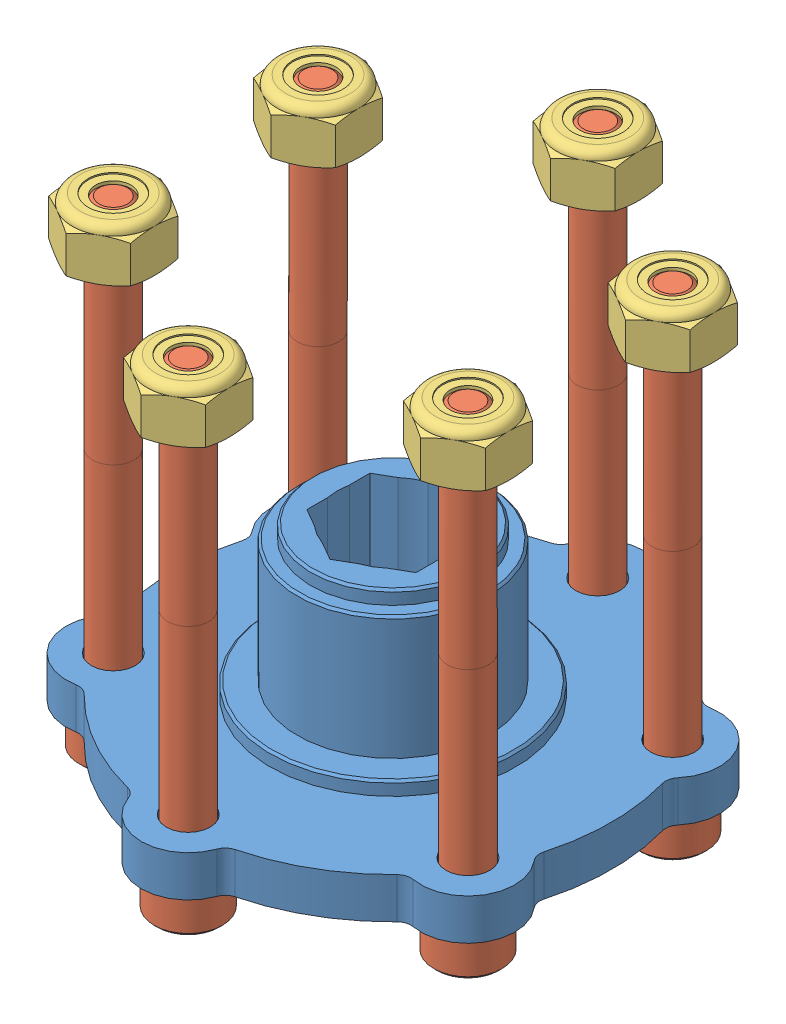
SolidWorks assembly GE-22447, configuration Default. Lengths in mm.
Overall size (76.79 56.16 74.45).
17 component instances, 5 part files, 35 mates.
Components (placement in the parent):
- GE-22446-1: GE-22446 [Default] at origin
  - Tire-1: Tire [Default] x (-1 0 0) z (0 -1 0) (suppressed, hidden)
  - Valve-1: Valve [Default] at (-45.72 0 0) x (-1 0 0) z (0 0 -1) (suppressed, hidden)
  - Pneumatic Hub-1: Pneumatic Hub [Default] at (-1.1351 -5.8811 9.0791) x (0 -1 0) z (0 0 -1) size (45.47 106.55 106.55) (suppressed, hidden)
- GE-22436-1: GE-22436 [am-4124 500 Hex Hub] at (-12.31 -22.733 37.2255) x (0.866025 0 -0.5) z (0 1 0) size (58.55 52.17 25.4)
- socket_hex_10_32_2_partial-1: socket_hex_10_32_2_partial [Default] at (0 23.3045 23.8125) x (-0.837169 0 -0.546944) z (0 1 0) size (7.92 7.92 55.85)
- nylock_10_32-1: nylock_10_32 [90631A411] at (0 17.653 23.8125) size (9.53 5.95 11)
- socket_hex_10_32_2_partial-2: socket_hex_10_32_2_partial [Default] at (20.6222 23.3045 11.9062) x (-0.925243 0 -0.379375) z (0 1 0) size (7.92 7.92 55.85)
- nylock_10_32-2: nylock_10_32 [90631A411] at (20.6222 17.653 11.9062) size (9.53 5.95 11)
- socket_hex_10_32_2_partial-4: socket_hex_10_32_2_partial [Default] at (20.6222 23.3045 -11.9062) x (-0.980159 0 -0.198211) z (0 1 0) size (7.92 7.92 55.85)
- nylock_10_32-4: nylock_10_32 [90631A411] at (20.6222 17.653 -11.9062) x (0.5 0 -0.866025) z (0.866025 0 0.5) size (9.53 5.95 11)
- socket_hex_10_32_2_partial-6: socket_hex_10_32_2_partial [Default] at (0 23.3045 -23.8125) x (-0.999843 0 0.017745) z (0 1 0) size (7.92 7.92 55.85)
- nylock_10_32-6: nylock_10_32 [90631A411] at (0 17.653 -23.8125) x (0.5 0 -0.866025) z (0.866025 0 0.5) size (9.53 5.95 11)
- socket_hex_10_32_2_partial-8: socket_hex_10_32_2_partial [Default] at (-20.6222 23.3045 -11.9062) x (0.379375 0 -0.925243) z (0 1 0) size (7.92 7.92 55.85)
- nylock_10_32-8: nylock_10_32 [90631A411] at (-20.6222 17.653 -11.9062) x (0.5 0 -0.866025) z (0.866025 0 0.5) size (9.53 5.95 11)
- socket_hex_10_32_2_partial-10: socket_hex_10_32_2_partial [Default] at (-20.6222 23.3045 11.9062) x (-0.879729 0 0.475475) z (0 1 0) size (7.92 7.92 55.85)
- nylock_10_32-10: nylock_10_32 [90631A411] at (-20.6222 17.653 11.9062) size (9.53 5.95 11)
Mates (geometry in assembly coordinates):
- Coincident1: coincident aligned: plane of am-0970 8IN Pneumatic Wheel-1 through (0 0 0) normal (0 1 0)
- Coincident2: coincident aligned: plane of am-0970 8IN Pneumatic Wheel-1 through (0 0 0) normal (0 0 1)
- Coincident3: coincident aligned: plane of am-0970 8IN Pneumatic Wheel-1 through (0 0 0) normal (1 0 0)
- Concentric1: concentric aligned: cylinder of am-0970 8IN Pneumatic Wheel-1/Pneumatic Hub-1/Hub-2 through (0 -13.208 0) axis (0 -1 0) radius 14.2875; cylinder of GE-22436-1 through (0 -6.858 0) axis (0 -1 0) radius 11.1125
- Concentric2: concentric anti-aligned: cylinder of am-0970 8IN Pneumatic Wheel-1/Pneumatic Hub-1/Hub-2 through (20.6222 0.3627 11.9062) axis (0 -1 0) radius 2.54; cylinder of GE-22436-1 through (20.6222 -22.733 11.9062) axis (0 1 0) radius 2.5527
- Coincident4: coincident anti-aligned: plane of am-0970 8IN Pneumatic Wheel-1/Pneumatic Hub-1/Hub-2 through (0 -22.733 0) normal (0 -1 0); plane of GE-22436-1 through (-10.3111 -22.733 5.9531) normal (0 1 0)
- Concentric3: concentric aligned: cylinder of GE-22436-1 through (0 -22.733 23.8125) axis (0 1 0) radius 2.5527; cylinder of socket_hex_10_32_2_partial-1 through (0 -27.4955 23.8125) axis (0 1 0) radius 2.413
- Coincident5: coincident anti-aligned: plane of GE-22436-1 through (-10.3111 -27.4955 5.9531) normal (0 -1 0); plane of socket_hex_10_32_2_partial-1 through (0 -27.4955 23.8125) normal (0 1 0)
- Concentric4: concentric anti-aligned: cylinder of socket_hex_10_32_2_partial-1 through (0 -27.4955 23.8125) axis (0 1 0) radius 2.413; cylinder of nylock_10_32-1 through (0 15.24 23.8125) axis (0 -1 0) radius 2.413
- Coincident6: coincident anti-aligned: plane of am-0970 8IN Pneumatic Wheel-1/Pneumatic Hub-1/Hub-1 through (0 17.653 18.3132) normal (0 1 0); plane of nylock_10_32-1 through (0 17.653 18.3132) normal (0 -1 0)
- Concentric5: concentric anti-aligned: cylinder of socket_hex_10_32_2_partial-2 through (20.6222 -27.4955 11.9062) axis (0 1 0) radius 2.413; cylinder of nylock_10_32-2 through (20.6222 15.24 11.9062) axis (0 -1 0) radius 2.413
- Concentric6: concentric aligned: cylinder of GE-22436-1 through (20.6222 -22.733 11.9062) axis (0 1 0) radius 2.5527; cylinder of socket_hex_10_32_2_partial-2 through (20.6222 -27.4955 11.9062) axis (0 1 0) radius 2.413
- Coincident7: coincident anti-aligned: plane of GE-22436-1 through (-10.3111 -27.4955 5.9531) normal (0 -1 0); plane of socket_hex_10_32_2_partial-2 through (20.6222 -27.4955 11.9062) normal (0 1 0)
- Coincident8: coincident anti-aligned: plane of am-0970 8IN Pneumatic Wheel-1/Pneumatic Hub-1/Hub-1 through (15.8597 17.653 9.1566) normal (0 1 0); plane of nylock_10_32-2 through (20.6222 17.653 6.407) normal (0 -1 0)
- Parallel5: parallel: plane of nylock_10_32-2 through (15.8597 23.6061 9.1566) normal (-1 0 0); line of am-0970 8IN Pneumatic Wheel-1/Pneumatic Hub-1/Hub-1 through (15.6952 22.3653 14.7509) axis (0 0 -1)
- Concentric8: concentric anti-aligned: cylinder of socket_hex_10_32_2_partial-4 through (20.6222 -27.4955 -11.9062) axis (0 1 0) radius 2.413; cylinder of nylock_10_32-4 through (20.6222 15.24 -11.9062) axis (0 -1 0) radius 2.413
- Concentric9: concentric aligned: cylinder of GE-22436-1 through (20.6222 -22.733 -11.9062) axis (0 1 0) radius 2.5527; cylinder of socket_hex_10_32_2_partial-4 through (20.6222 -27.4955 -11.9062) axis (0 1 0) radius 2.413
- Coincident14: coincident anti-aligned: plane of GE-22436-1 through (-10.3111 -27.4955 5.9531) normal (0 -1 0); plane of socket_hex_10_32_2_partial-4 through (20.6222 -27.4955 -11.9062) normal (0 1 0)
- Coincident15: coincident anti-aligned: plane of am-0970 8IN Pneumatic Wheel-1/Pneumatic Hub-1/Hub-1 through (15.8597 17.653 -9.1566) normal (0 1 0); plane of nylock_10_32-4 through (15.8597 17.653 -14.6559) normal (0 -1 0)
- Parallel6: parallel: line of am-0970 8IN Pneumatic Wheel-1/Pneumatic Hub-1/Hub-1 through (20.6222 22.3653 -6.217) axis (-0.866025 0 -0.5); plane of nylock_10_32-4 through (15.8597 23.6061 -9.1566) normal (-0.5 0 0.866025)
- Concentric11: concentric anti-aligned: cylinder of socket_hex_10_32_2_partial-6 through (0 -27.4955 -23.8125) axis (0 1 0) radius 2.413; cylinder of nylock_10_32-6 through (0 15.24 -23.8125) axis (0 -1 0) radius 2.413
- Concentric12: concentric aligned: cylinder of GE-22436-1 through (0 -22.733 -23.8125) axis (0 1 0) radius 2.5527; cylinder of socket_hex_10_32_2_partial-6 through (0 -27.4955 -23.8125) axis (0 1 0) radius 2.413
- Coincident16: coincident anti-aligned: plane of GE-22436-1 through (-10.3111 -27.4955 5.9531) normal (0 -1 0); plane of socket_hex_10_32_2_partial-6 through (0 -27.4955 -23.8125) normal (0 1 0)
- Coincident17: coincident anti-aligned: plane of am-0970 8IN Pneumatic Wheel-1/Pneumatic Hub-1/Hub-1 through (0 17.653 -18.3132) normal (0 1 0); plane of nylock_10_32-6 through (-4.7625 17.653 -26.5621) normal (0 -1 0)
- Parallel7: parallel: line of am-0970 8IN Pneumatic Wheel-1/Pneumatic Hub-1/Hub-1 through (0 22.3653 -18.1232) axis (-0.866025 0 -0.5); plane of nylock_10_32-6 through (-4.7625 23.6061 -21.0629) normal (-0.5 0 0.866025)
- Concentric14: concentric anti-aligned: cylinder of socket_hex_10_32_2_partial-8 through (-20.6222 -27.4955 -11.9062) axis (0 1 0) radius 2.413; cylinder of nylock_10_32-8 through (-20.6222 15.24 -11.9062) axis (0 -1 0) radius 2.413
- Concentric15: concentric anti-aligned: cylinder of GE-22436-1 through (-20.6222 -27.4955 -11.9062) axis (0 -1 0) radius 2.5527; cylinder of socket_hex_10_32_2_partial-8 through (-20.6222 -27.4955 -11.9062) axis (0 1 0) radius 2.413
- Coincident18: coincident anti-aligned: plane of GE-22436-1 through (-10.3111 -27.4955 5.9531) normal (0 -1 0); plane of socket_hex_10_32_2_partial-8 through (-20.6222 -27.4955 -11.9062) normal (0 1 0)
- Coincident19: coincident anti-aligned: plane of am-0970 8IN Pneumatic Wheel-1/Pneumatic Hub-1/Hub-1 through (-15.8597 17.653 -9.1566) normal (0 1 0); plane of nylock_10_32-8 through (-25.3847 17.653 -14.6559) normal (0 -1 0)
- Parallel8: parallel: line of am-0970 8IN Pneumatic Wheel-1/Pneumatic Hub-1/Hub-1 through (-20.6222 22.3653 -6.217) axis (-0.866025 0 -0.5); plane of nylock_10_32-8 through (-25.3847 23.6061 -9.1566) normal (-0.5 0 0.866025)
- Concentric17: concentric anti-aligned: cylinder of socket_hex_10_32_2_partial-10 through (-20.6222 -27.4955 11.9062) axis (0 1 0) radius 2.413; cylinder of nylock_10_32-10 through (-20.6222 15.24 11.9062) axis (0 -1 0) radius 2.413
- Concentric18: concentric aligned: cylinder of GE-22436-1 through (-20.6222 -22.733 11.9062) axis (0 1 0) radius 2.5527; cylinder of socket_hex_10_32_2_partial-10 through (-20.6222 -27.4955 11.9062) axis (0 1 0) radius 2.413
- Coincident20: coincident anti-aligned: plane of GE-22436-1 through (-10.3111 -27.4955 5.9531) normal (0 -1 0); plane of socket_hex_10_32_2_partial-10 through (-20.6222 -27.4955 11.9062) normal (0 1 0)
- Coincident21: coincident anti-aligned: plane of am-0970 8IN Pneumatic Wheel-1/Pneumatic Hub-1/Hub-1 through (-15.8597 17.653 9.1566) normal (0 1 0); plane of nylock_10_32-10 through (-20.6222 17.653 6.407) normal (0 -1 0)
- Parallel9: parallel: line of am-0970 8IN Pneumatic Wheel-1/Pneumatic Hub-1/Hub-1 through (-25.5493 22.3653 14.7509) axis (0 0 -1); plane of nylock_10_32-10 through (-25.3847 23.6061 9.1566) normal (-1 0 0)
